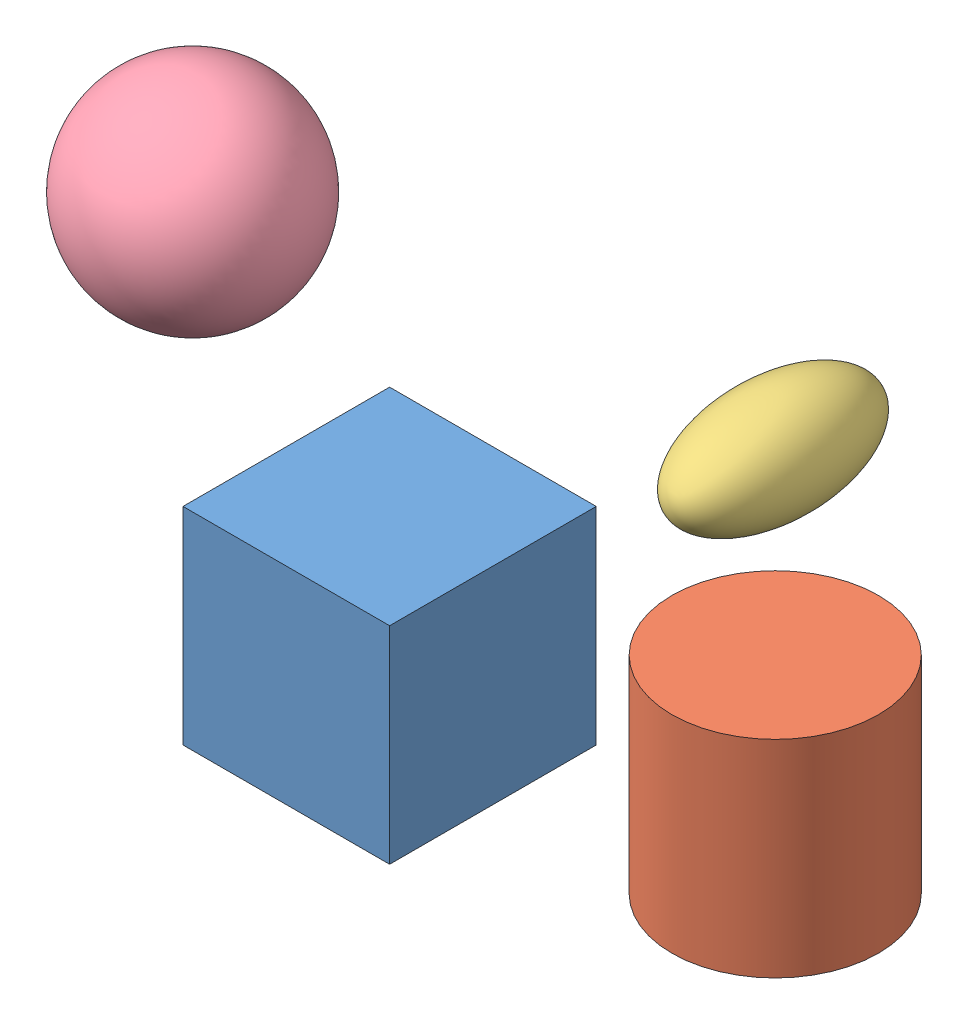
SolidWorks assembly Assem1, configuration Default. Lengths in mm.
Overall size (86.32 62.28 58.81).
4 component instances, 4 part files, 0 mates.
Components (placement in the parent):
- cube-1: cube [Default] at (6.6734 13.3062 20.9436) size (25.4 25.4 25.4)
- cylinder-1: cylinder [Default] at (33.7742 0.8835 0.6444) size (25.4 25.4 25.4)
- ellipsoid-1: ellipsoid [Default] at (20.391 22.2356 -12.4671) size (12.7 12.7 25.4)
- sphere-1: sphere [Default] at (-27.1472 37.7675 11.3379) size (25.4 25.4 25.4)
